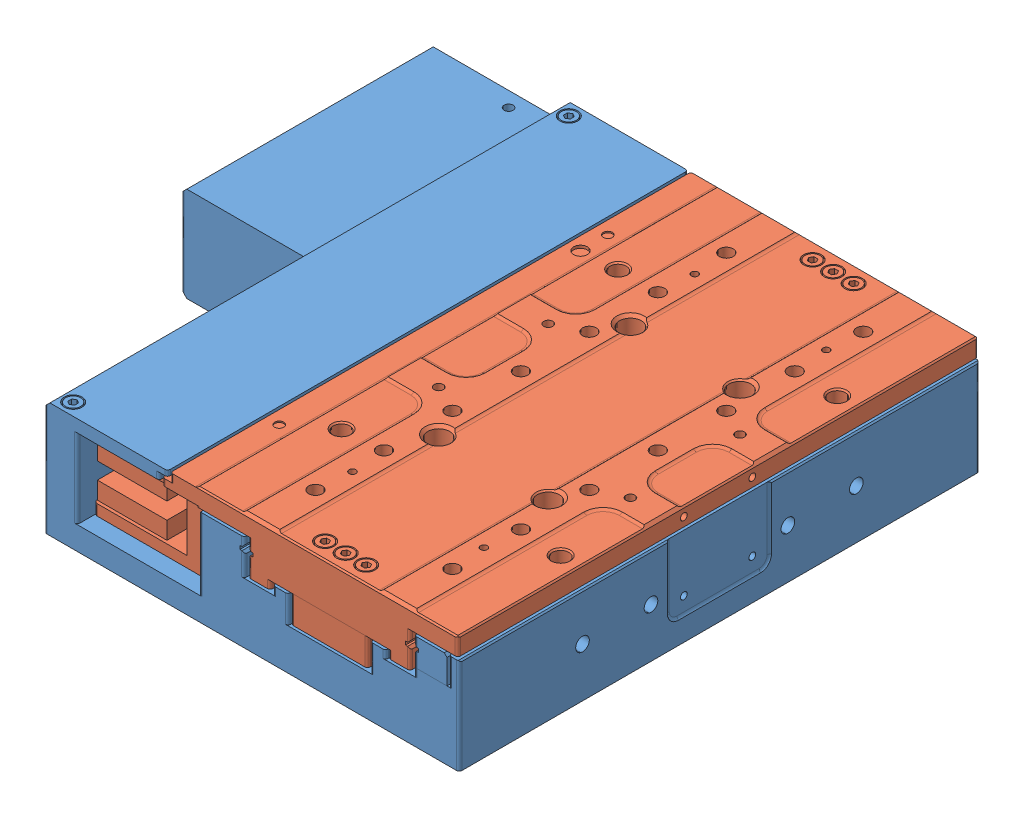
SolidWorks assembly LDM, configuration LDM060C-AE54T10A. Lengths in mm.
Overall size (206.26 44.16 190).
2 component instances, 2 part files, 6 mates.
Components (placement in the parent):
- LDM_base^LDM-2: LDM_base^LDM [LDM060-T10] at origin size (206.26 43 190) (virtual)
- LDM_carriage^LDM-2: LDM_carriage^LDM [LDM060] at origin (virtual)
Mates (geometry in assembly coordinates):
- Coincident1: coincident aligned: plane of LDM_carriage^LDM-2 through (0 0 0) normal (1 0 0); plane of assembly through (0 0 0) normal (1 0 0)
- Coincident2: coincident aligned: plane of LDM_carriage^LDM-2 through (0 0 0) normal (0 1 0); plane of LDM_base^LDM-2 through (0 0 0) normal (0 1 0)
- LimitDistance1: limit distance = 0 mm aligned: plane of LDM_carriage^LDM-2 through (0 0 0) normal (0 0 1); plane of LDM_base^LDM-2 through (0 0 0) normal (0 0 1)
- Coincident3: coincident aligned: plane of LDM_base^LDM-2 through (0 0 0) normal (1 0 0); plane of assembly through (0 0 0) normal (1 0 0)
- Coincident4: coincident anti-aligned: plane of LDM_base^LDM-2; plane of assembly through (0 0 0) normal (0 1 0)
- Coincident5: coincident aligned: plane of LDM_base^LDM-2; plane of assembly through (0 0 0) normal (0 0 1)
